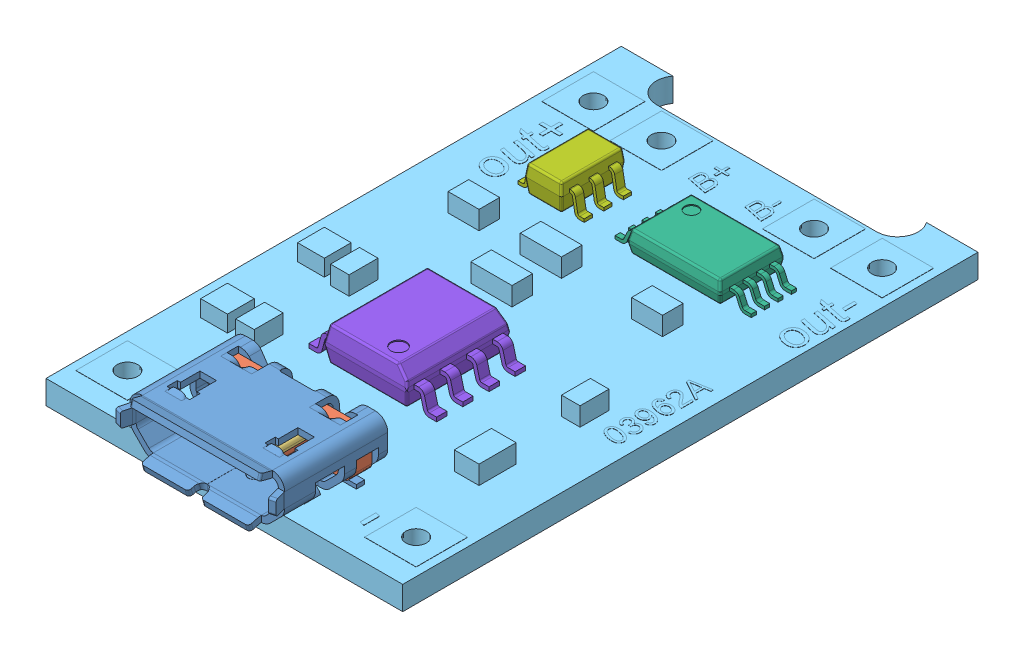
SolidWorks assembly Плата ЗУ TP4056(03962A), configuration По умолчанию. Lengths in mm.
Overall size (17.3 3.8 29.35).
13 component instances, 8 part files, 13 mates.
Components (placement in the parent):
- Копия micro_usb_connector^Плата ЗУ TP4056(03962A)-1: Копия micro_usb_connector^Плата ЗУ TP4056(03962A) [По умолчанию] at (4.4684 3.5679 3.8034) x (0 0 1) z (0 1 0) size (5.84 7.77 3.44) (virtual)
  - Копия shield^Копия micro_usb_connector_Плата ЗУ TP4056(03962A)-1: Копия shield^Копия micro_usb_connector_Плата ЗУ TP4056(03962A) [По умолчанию] at origin size (5.84 7.77 3.44) (virtual)
  - Копия socket_housing^Копия micro_usb_connector_Плата ЗУ TP4056(03962A)-1: Копия socket_housing^Копия micro_usb_connector_Плата ЗУ TP4056(03962A) [По умолчанию] at origin size (4.24 6.85 2.15) (virtual)
  - Копия socket_plate^Копия micro_usb_connector_Плата ЗУ TP4056(03962A)-1: Копия socket_plate^Копия micro_usb_connector_Плата ЗУ TP4056(03962A) [По умолчанию] at origin size (3.38 6.8 0.31) (virtual)
  - Копия terminal^Копия micro_usb_connector_Плата ЗУ TP4056(03962A)-2: Копия terminal^Копия micro_usb_connector_Плата ЗУ TP4056(03962A) [По умолчанию] at (0 -1.3 0) size (3.22 0.35 1.72) (virtual)
  - Копия terminal^Копия micro_usb_connector_Плата ЗУ TP4056(03962A)-6: Копия terminal^Копия micro_usb_connector_Плата ЗУ TP4056(03962A) [По умолчанию] at (0 -0.65 0) size (3.22 0.35 1.72) (virtual)
  - Копия terminal^Копия micro_usb_connector_Плата ЗУ TP4056(03962A)-7: Копия terminal^Копия micro_usb_connector_Плата ЗУ TP4056(03962A) [По умолчанию] at origin size (3.22 0.35 1.72) (virtual)
  - Копия terminal^Копия micro_usb_connector_Плата ЗУ TP4056(03962A)-8: Копия terminal^Копия micro_usb_connector_Плата ЗУ TP4056(03962A) [По умолчанию] at (0 0.65 0) size (3.22 0.35 1.72) (virtual)
  - Копия terminal^Копия micro_usb_connector_Плата ЗУ TP4056(03962A)-9: Копия terminal^Копия micro_usb_connector_Плата ЗУ TP4056(03962A) [По умолчанию] at (0 1.3 0) size (3.22 0.35 1.72) (virtual)
- Деталь11^Плата ЗУ TP4056(03962A)-1: Деталь11^Плата ЗУ TP4056(03962A) [По умолчанию] at (4.4684 3.5679 3.8034) x (0 0 1) z (0 1 0) size (27.9 17.3 2.06) (virtual)
- Копия MO-153AA^Плата ЗУ TP4056(03962A)-1: Копия MO-153AA^Плата ЗУ TP4056(03962A) [По умолчанию] at (7.0684 3.5679 -14.7726) x (0 0 1) z (0 1 0) size (3.1 6.6 1.2) (virtual)
- Копия SC-74^Плата ЗУ TP4056(03962A)-1: Копия SC-74^Плата ЗУ TP4056(03962A) [По умолчанию] at (0.7184 3.5679 -14.7726) x (0 0 -1) z (0 1 0) size (3.1 3.2 1.45) (virtual)
- Копия MS-012AA^Плата ЗУ TP4056(03962A)-1: Копия MS-012AA^Плата ЗУ TP4056(03962A) [По умолчанию] at (4.0184 3.5679 -3.8226) x (0 0 -1) z (0 1 0) size (5 6.2 1.75) (virtual)
Mates (geometry in assembly coordinates):
- На месте1: in place: plane of ? through (4.4684 3.5679 3.8034) normal (0 1 0); plane of ? through (4.4684 3.5679 3.8034) normal (0 1 0); moOrthogonalPlaneRef_w of ? through (4.4684 3.5679 3.8034) normal (0 1 0); unknown of ?; plane of ? through (4.4684 3.5679 3.8034) normal (0 1 0); unknown of ?; plane of ? through (4.4684 3.5679 3.8034) normal (0 1 0); unknown of ?
- Совпадение1: coincident aligned: plane of ?; plane of ?
- Совпадение2: coincident aligned: moOrthogonalPlaneRef_w of ?; plane of ?
- Совпадение3: coincident anti-aligned: moOrthogonalPlaneRef_w of ?; plane of ?
- Совпадение1: coincident anti-aligned: plane of Деталь11^Плата ЗУ TP4056(03962A)-1 through (4.4684 3.5679 3.8034) normal (0 1 0); plane of Копия MO-153AA^Плата ЗУ TP4056(03962A)-1 through (10.3684 3.5679 -13.6726) normal (0 -1 0)
- Расстояние1: distance = 4 mm aligned: plane of Копия MO-153AA^Плата ЗУ TP4056(03962A)-1 through (9.3184 4.1679 -16.3226) normal (0 0 -1); plane of Деталь11^Плата ЗУ TP4056(03962A)-1 through (4.4684 2.4179 -20.3226) normal (0 0 -1)
- Расстояние2: distance = 3.8 mm aligned: plane of Деталь11^Плата ЗУ TP4056(03962A)-1 through (13.1184 2.4179 3.8034) normal (1 0 0); plane of Копия MO-153AA^Плата ЗУ TP4056(03962A)-1 through (9.3184 4.1679 -13.2226) normal (1 0 0)
- Совпадение2: coincident anti-aligned: plane of Деталь11^Плата ЗУ TP4056(03962A)-1 through (4.4684 3.5679 3.8034) normal (0 1 0); plane of Копия SC-74^Плата ЗУ TP4056(03962A)-1 through (-0.6663 3.5679 -15.9226) normal (0 -1 0)
- Расстояние3: distance = 4 mm: plane of Деталь11^Плата ЗУ TP4056(03962A)-1 through (4.4684 2.4179 -20.3226) normal (0 0 -1); line of Копия SC-74^Плата ЗУ TP4056(03962A)-1 through (1.5192 4.4679 -16.3226) axis (-1 0 0)
- Расстояние4: distance = 4 mm: plane of Деталь11^Плата ЗУ TP4056(03962A)-1 through (-4.1816 2.4179 3.8034) normal (-1 0 0); line of Копия SC-74^Плата ЗУ TP4056(03962A)-1 through (-0.1816 4.4679 -16.2234) axis (0 0 1)
- Совпадение3: coincident anti-aligned: plane of Деталь11^Плата ЗУ TP4056(03962A)-1 through (4.4684 3.5679 3.8034) normal (0 1 0); plane of Копия MS-012AA^Плата ЗУ TP4056(03962A)-1 through (0.9184 3.5679 -2.1676) normal (0 -1 0)
- Расстояние5: distance = 6.2 mm aligned: plane of Копия MS-012AA^Плата ЗУ TP4056(03962A)-1 through (2.0184 4.3929 -6.3226) normal (-1 0 0); plane of Деталь11^Плата ЗУ TP4056(03962A)-1 through (-4.1816 2.4179 3.8034) normal (-1 0 0)
- Расстояние6: distance = 14 mm aligned: plane of Копия MS-012AA^Плата ЗУ TP4056(03962A)-1 through (6.0184 4.3929 -6.3226) normal (0 0 -1); plane of Деталь11^Плата ЗУ TP4056(03962A)-1 through (4.4684 2.4179 -20.3226) normal (0 0 -1)
